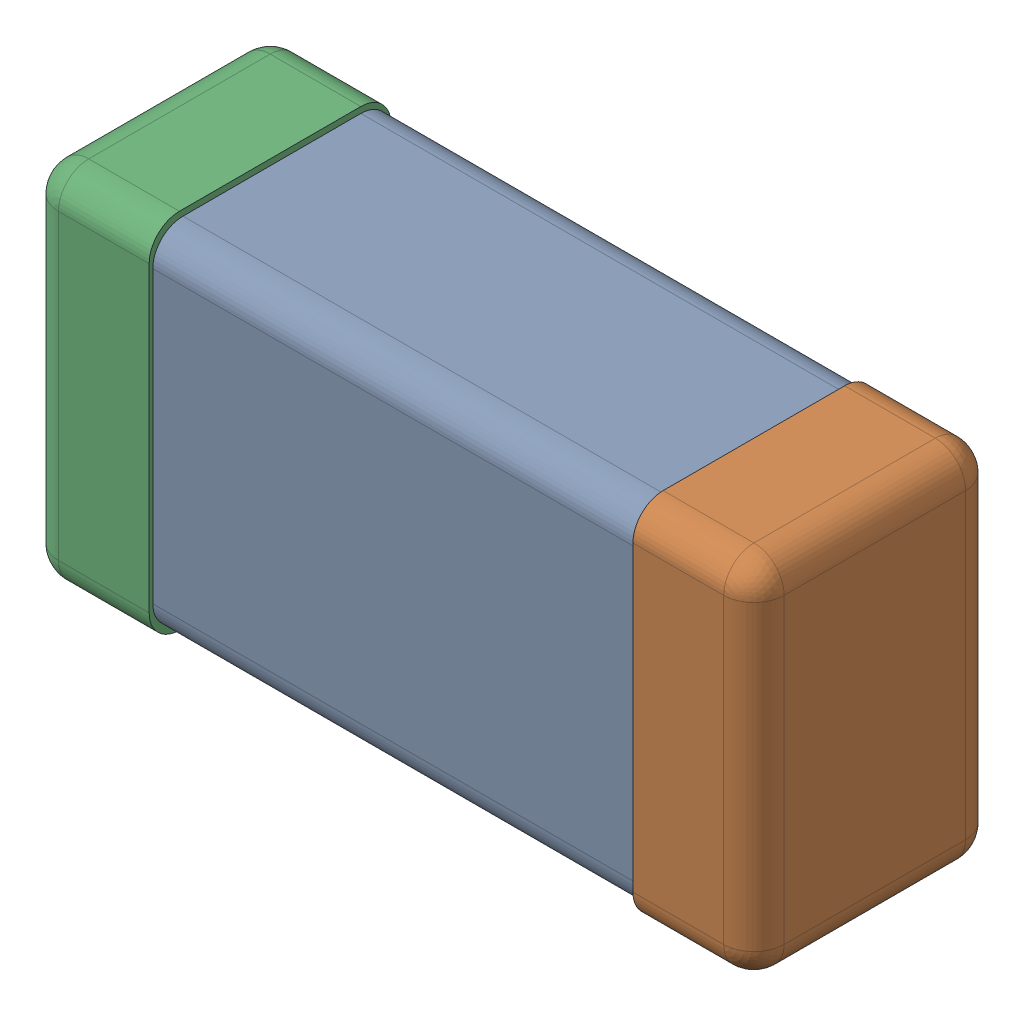
SolidWorks assembly C0201_020_31, configuration Standard. Lengths in mm.
Overall size (0.6 0.3 0.2).
3 component instances, 3 part files, 0 mates.
Components (placement in the parent):
- Part 3_2-1: Part 3_2 [Standard] at (0 0 -7.3015) size (0.5 0.29 0.2)
- Part 2_2-1: Part 2_2 [Standard] at (0 0 -7.3) size (0.1 0.3 0.2)
- Part 1_2-1: Part 1_2 [Standard] at (0 0 -7.3) size (0.1 0.3 0.2)
